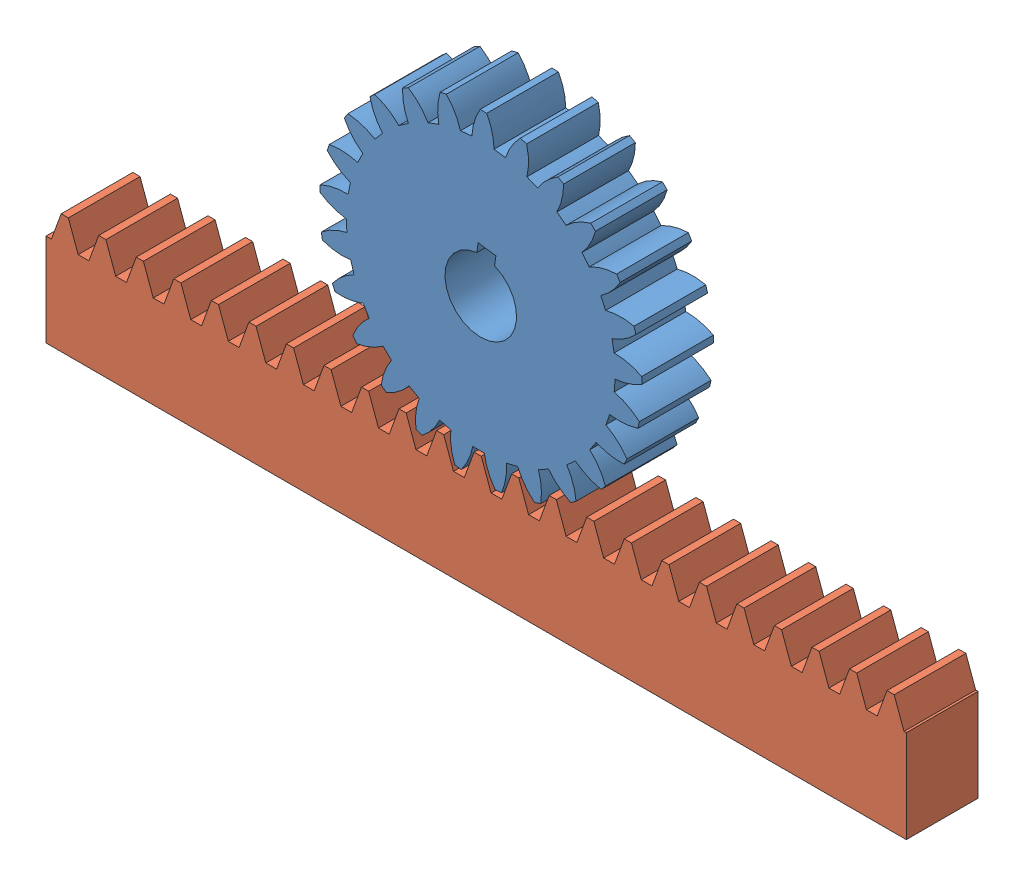
SolidWorks assembly STA3, configuration Default. Lengths in mm.
Overall size (304.8 155.79 25.4).
2 component instances, 2 part files, 6 mates.
Components (placement in the parent):
- spur gear_ai-4: spur gear_ai [Inch - Spur gear 6DP 25T 20PA 1FW ---S25N3.0H2.0L1.0S1] x (0 0 1) z (-0.989908 0.141715 0) size (25.4 113.98 114.2)
- rack spur rectangular_ai-2: rack spur rectangular_ai [Inch - Rack-spur - rectangular 6DP 20PA 1FW 1.5PH 12L---SAll] at (-154.037 -91.44 25.4) size (304.8 42.33 25.4)
Mates (geometry in assembly coordinates):
- Coincident19: coincident: plane of spur gear_ai-4 through (0 0 0) normal (0 0 -1); plane of assembly through (0 0 0) normal (0 0 1)
- Concentric7: concentric: circle of spur gear_ai-4; circle of assembly
- Coincident20: coincident: plane of spur gear_ai-4 through (0 0 0) normal (0 0 -1); plane of rack spur rectangular_ai-2 through (-154.037 -49.1067 0) normal (0 0 -1)
- Coincident21: coincident: line of rack spur rectangular_ai-2 through (304.8 -154.037 -91.44) axis (0 1 0); line of assembly
- RackPinionMate4: rack pinion = 254 mm: line of rack spur rectangular_ai-2 through (304.8 -154.037 -91.44) axis (0 1 0); circle of spur gear_ai-4
- Lock1: lock: unknown of spur gear_ai-4; unknown of rack spur rectangular_ai-2
